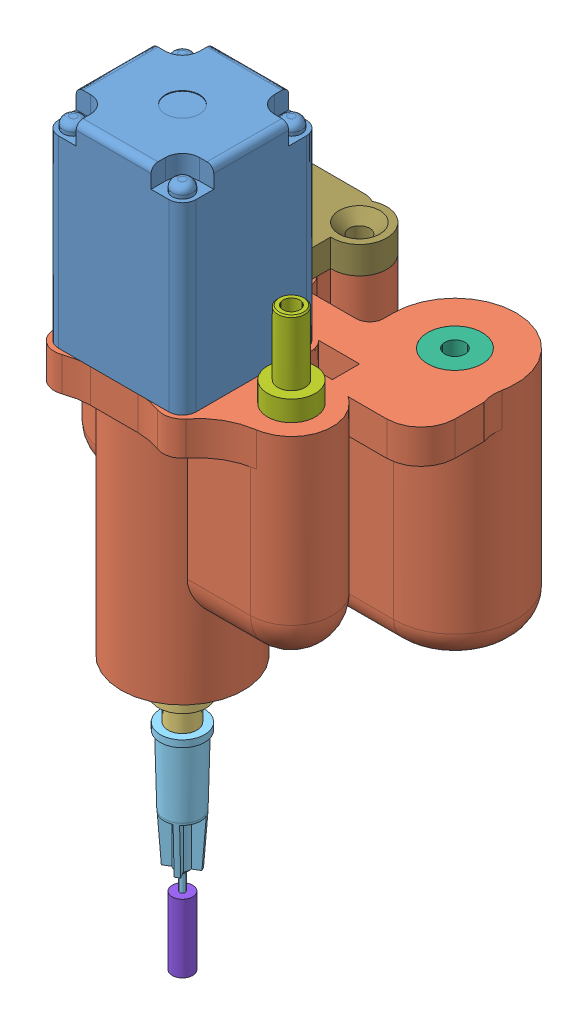
SolidWorks assembly Vacuum manipulator, configuration По умолчанию. Lengths in mm.
Overall size (60 110 38.83).
14 component instances, 12 part files, 28 mates.
Components (placement in the parent):
- FL20STH30-0604A-1: FL20STH30-0604A [По умолчанию] at (0 10.1 -10.1) x (1 0 0) z (0 -1 0) size (20.2 20.2 45)
- Vacuum connector-1: Vacuum connector [По умолчанию] at (0 -19.9 -10.1) x (1 0 0) z (0 0 -1) size (60 40 38.83)
- Vacuum manipulator axis-1: Vacuum manipulator axis [По умолчанию] at (0 -39.1192 -10.1) x (0.991916 0 0.126893) z (-0.126893 0 0.991916) size (13 52.5 13)
- Silicone gasket-1: Silicone gasket [По умолчанию] at (0 -39.9 -10.1) x (0.962843 0 -0.270063) z (0 1 0) size (13 13 5)
- Silicone gasket-2: Silicone gasket [По умолчанию] at (0 -54.9 -10.1) x (0.992934 0 -0.118668) z (0 1 0) size (13 13 5)
- Syringe needle-1: Syringe needle [По умолчанию] at (0 -68.4 -10.1) x (0.516653 0 0.856195) z (-0.856195 0 0.516653) size (6.5 31 6.5)
- PTFE Z bushing-1: PTFE Z bushing [По умолчанию] at (-21 -53.9 -29.1) x (1 0 0) z (0 1 0) size (8 8 34)
- PTFE Z bushing-2: PTFE Z bushing [По умолчанию] at (21 -53.9 -29.1) x (1 0 0) z (0 1 0) size (8 8 34)
- Vacuum connectoe union-1: Vacuum connectoe union [По умолчанию] at (16 -7.4 -10.1) x (1 0 0) z (0 -1 0) size (7 7 25)
- Silicone cap-1: Silicone cap [По умолчанию] at (0 -99.9 -10.1) x (1 0 0) z (0 1 0) size (3 3 10)
- Vacoom connector fixing washer-2: Vacoom connector fixing washer [По умолчанию] at (0 -59.9 -10.1) x (0.897919 0 -0.440161) z (0 1 0) size (13 13 5)
- Z belt spring-1: Z belt spring [По умолчанию] at (-7.25 -34.9 -29.1) x (0.706502 0 0.707711) z (0 -1 0) size (11.12 11.15 15.02)
- Belt fixer-1: Belt fixer [По умолчанию] at (-7.25 -34.9 -29.1) x (-0.144268 0 -0.989539) z (0 1 0) size (11 11 15)
- Vacoom connector cup-1: Vacoom connector cup [По умолчанию] at (-5.75 -15.9 -29.6632) x (1 0 0) z (0 -1 0) size (25.79 19.09 4)
Mates (geometry in assembly coordinates):
- Концентричный1: concentric anti-aligned: cylinder of FL20STH30-0604A-1 through (0 -34.9 -10.1) axis (0 1 0) radius 2; cylinder of Vacuum connector-1 through (0 -19.9 -10.1) axis (0 -1 0) radius 6.5
- Совпадение1: coincident anti-aligned: plane of FL20STH30-0604A-1 through (0 -19.9 -10.1) normal (0 -1 0); plane of Vacuum connector-1 through (0 -19.9 -10.1) normal (0 1 0)
- Параллельность1: parallel aligned: plane of FL20STH30-0604A-1 through (10.1 -19.9 0) normal (0 0 1); plane of Vacuum connector-1 through (10 -59.9 -0.1) normal (0 0 1)
- Концентричный2: concentric aligned: cylinder of FL20STH30-0604A-1 through (0 -34.9 -10.1) axis (0 1 0) radius 2; cylinder of Vacuum manipulator axis-1 through (0 -21.4 -10.1) axis (0 1 0) radius 2
- Совпадение3: coincident anti-aligned: plane of FL20STH30-0604A-1 through (0 -21.4 -10.1) normal (0 -1 0); plane of Vacuum manipulator axis-1 through (-1.9838 -21.4 -10.3538) normal (0 1 0)
- Совпадение4: coincident aligned: plane of FL20STH30-0604A-1 through (10.1 -19.9 0) normal (0 0 1); plane of assembly through (0 0 0) normal (0 0 1)
- Концентричный3: concentric aligned: cylinder of Silicone gasket-1 through (0 -34.9 -10.1) axis (0 -1 0) radius 3.5; cylinder of Silicone gasket-2 through (0 -49.9 -10.1) axis (0 -1 0) radius 3.5
- Концентричный4: concentric anti-aligned: cylinder of Vacuum manipulator axis-1 through (0 -21.4 -10.1) axis (0 1 0) radius 3.5; cylinder of Silicone gasket-1 through (0 -34.9 -10.1) axis (0 -1 0) radius 3.5
- Совпадение5: coincident anti-aligned: plane of Vacuum manipulator axis-1 through (-6.4475 -34.9 -10.9248) normal (0 -1 0); plane of Silicone gasket-1 through (0 -34.9 -10.1) normal (0 1 0)
- Совпадение6: coincident anti-aligned: plane of Vacuum connector-1 through (0 -49.9 -10.1) normal (0 -1 0); plane of Silicone gasket-2 through (0 -49.9 -10.1) normal (0 1 0)
- Концентричный6: concentric anti-aligned: cone of Vacuum manipulator axis-1 through (0 -64.9 -10.1) axis (0 -1 0); cylinder of Syringe needle-1 through (0 -68.4 -10.1) axis (0 1 0) radius 0.4
- Расстояние1: distance = 3.5 mm anti-aligned: plane of Vacuum manipulator axis-1 through (-3.4717 -64.9 -10.5441) normal (0 -1 0); plane of Syringe needle-1 through (-1.085 -68.4 -11.898) normal (0 1 0)
- Концентричный8: concentric anti-aligned: cylinder of Vacuum connector-1 through (-21 -59.9 -29.1) axis (0 1 0) radius 4; cylinder of PTFE Z bushing-1 through (-21 -19.9 -29.1) axis (0 -1 0) radius 4
- Совпадение9: coincident aligned: plane of Vacuum connector-1 through (0 -19.9 -10.1) normal (0 1 0); plane of PTFE Z bushing-1 through (-21 -19.9 -29.1) normal (0 1 0)
- Совпадение10: coincident aligned: plane of Vacuum connector-1 through (0 -19.9 -10.1) normal (0 1 0); plane of PTFE Z bushing-2 through (21 -19.9 -29.1) normal (0 1 0)
- Концентричный10: concentric aligned: cylinder of Vacuum connector-1 through (16 -43.9 -10.1) axis (0 1 0) radius 1.5; cylinder of Vacuum connectoe union-1 through (16 -32.4 -10.1) axis (0 1 0) radius 2
- Совпадение11: coincident anti-aligned: plane of Vacuum connector-1 through (0 -19.9 -10.1) normal (0 1 0); plane of Vacuum connectoe union-1 through (16 -19.9 -10.1) normal (0 -1 0)
- Концентричный11: concentric anti-aligned: cylinder of Vacuum connector-1 through (21 -59.9 -29.1) axis (0 1 0) radius 4; cylinder of PTFE Z bushing-2 through (21 -19.9 -29.1) axis (0 -1 0) radius 4
- Концентричный12: concentric anti-aligned: cylinder of Syringe needle-1 through (0 -68.4 -10.1) axis (0 1 0) radius 0.4; cylinder of Silicone cap-1 through (0 -89.9 -10.1) axis (0 -1 0) radius 0.4
- Расстояние2: distance = 0.5 mm aligned: plane of Syringe needle-1 through (-0.2067 -99.4 -10.4425) normal (0 -1 0); plane of Silicone cap-1 through (0 -99.9 -10.1) normal (0 -1 0)
- Концентричный13: concentric anti-aligned: cylinder of Vacuum manipulator axis-1 through (0 -21.4 -10.1) axis (0 1 0) radius 3.5; cylinder of Vacoom connector fixing washer-2 through (0 -54.9 -10.1) axis (0 -1 0) radius 4
- Совпадение12: coincident aligned: plane of Vacuum connector-1 through (0 -59.9 -10.1) normal (0 -1 0); plane of Vacoom connector fixing washer-2 through (0 -59.9 -10.1) normal (0 -1 0)
- Концентричный14: concentric anti-aligned: cylinder of Vacuum connector-1 through (-7.25 -48.9 -29.1) axis (0 1 0) radius 6.5; line of Z belt spring-1 through (-7.25 -34.9 -29.1) axis (0 -1 0)
- Совпадение18: coincident anti-aligned: plane of Vacuum connector-1 through (-7.25 -48.9 -29.1) normal (0 1 0); plane of Z belt spring-1 through (-9.3816 -48.9 -17.081) normal (0 -1 0)
- Концентричный15: concentric anti-aligned: cylinder of Vacuum connector-1 through (-7.25 -48.9 -29.1) axis (0 1 0) radius 6.5; cylinder of Belt fixer-1 through (-7.25 -19.9 -29.1) axis (0 -1 0) radius 5.5
- Совпадение19: coincident anti-aligned: plane of Z belt spring-1 through (-9.3816 -34.9 -17.081) normal (0 1 0); plane of Belt fixer-1 through (-7.25 -34.9 -29.1) normal (0 -1 0)
- Совпадение20: coincident anti-aligned: plane of Vacuum connector-1 through (0 -19.9 -10.1) normal (0 1 0); plane of Vacoom connector cup-1 through (1.9831 -19.9 -34.1) normal (0 -1 0)
- Совпадение22: coincident aligned: plane of Vacuum connector-1 through (1.75 -79.3558 -20.1) normal (1 0 0); plane of Vacoom connector cup-1 through (1.75 -19.9 -30.1068) normal (1 0 0)
